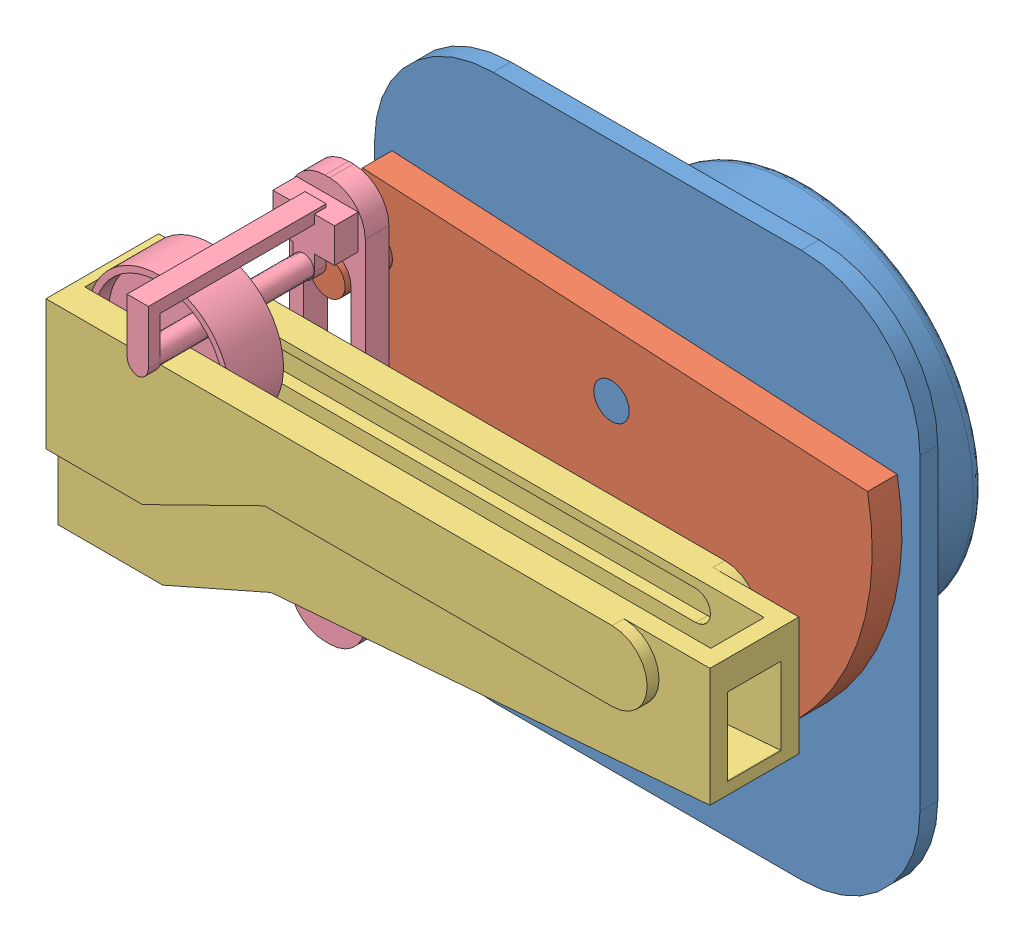
SolidWorks assembly Assem2, configuration Default. Lengths in mm.
Overall size (55 46 36.59).
4 component instances, 4 part files, 8 mates.
Components (placement in the parent):
- motor part-1: motor part [Default] at (22.8253 27.338 33.8506) size (46 46 16.59)
- lin 1-1: lin 1 [Default] at (22.3701 26.0327 35.8706) x (0.998501 -0.054733 0) z (0 0 1) size (44 27.36 6.5)
- IV roll controller-1: IV roll controller [Default] at (20.3768 27.2083 50.6206) size (55 17 9.5)
- roller-3: roller [Default] at (-0.0934 33.7083 49.1206) size (12.15 34.07 18)
Mates (geometry in assembly coordinates):
- Concentric1: concentric: cylinder of assembly; cylinder of assembly; cylinder of motor part-1 through (22.8253 34.338 38.3706) axis (0 0 -1) radius 1.5; cylinder of lin 1-1 through (22.8253 34.338 38.3706) axis (0 0 -1) radius 1.5
- Coincident1: coincident: plane of assembly; plane of assembly; plane of motor part-1 through (22.8253 34.338 38.3706) normal (0 0 1); plane of lin 1-1 through (22.8253 34.338 38.3706) normal (0 0 1)
- Slot2: slot: plane of roller-3 through (4.8553 12.6872 40.3706) normal (-1 0 0); cylinder of lin 1-1 through (2.8553 35.4326 42.3706) axis (0 0 -1) radius 1.5; cylinder of roller-3 through (2.8553 35.6872 40.3706) axis (0 0 1) radius 2
- Coincident8: coincident: plane of assembly; plane of assembly; plane of lin 1-1 through (2.8553 35.4326 42.3706) normal (0 0 1); plane of roller-3 through (2.6553 39.7643 42.3706) normal (0 0 1)
- Coincident9: coincident: plane of assembly; plane of assembly; plane of IV roll controller-1 through (20.3768 27.2083 53.6206) normal (0 0 -1); plane of roller-3 through (-0.0934 33.7083 53.6206) normal (0 0 1)
- Slot3: slot: cylinder of roller-3 through (-0.0934 33.7083 54.8706) axis (0 0 -1) radius 1.25; plane of IV roll controller-1 through (40.6736 32.4583 55.1206) normal (0 1 0); cylinder of IV roll controller-1 through (-0.1232 33.7083 55.1206) axis (0 0 -1) radius 1.25
- Parallel6: parallel: plane of assembly; plane of assembly; plane of motor part-1 through (-0.1747 50.338 35.3506) normal (0 1 0); plane of IV roll controller-1 through (20.3768 35.7083 55.1206) normal (0 1 0)
- Parallel7: parallel: plane of assembly; plane of assembly; plane of IV roll controller-1 through (-7.1232 27.2083 55.1206) normal (-1 0 0); plane of roller-3 through (-0.3447 11.692 40.3706) normal (-1 0 0)
